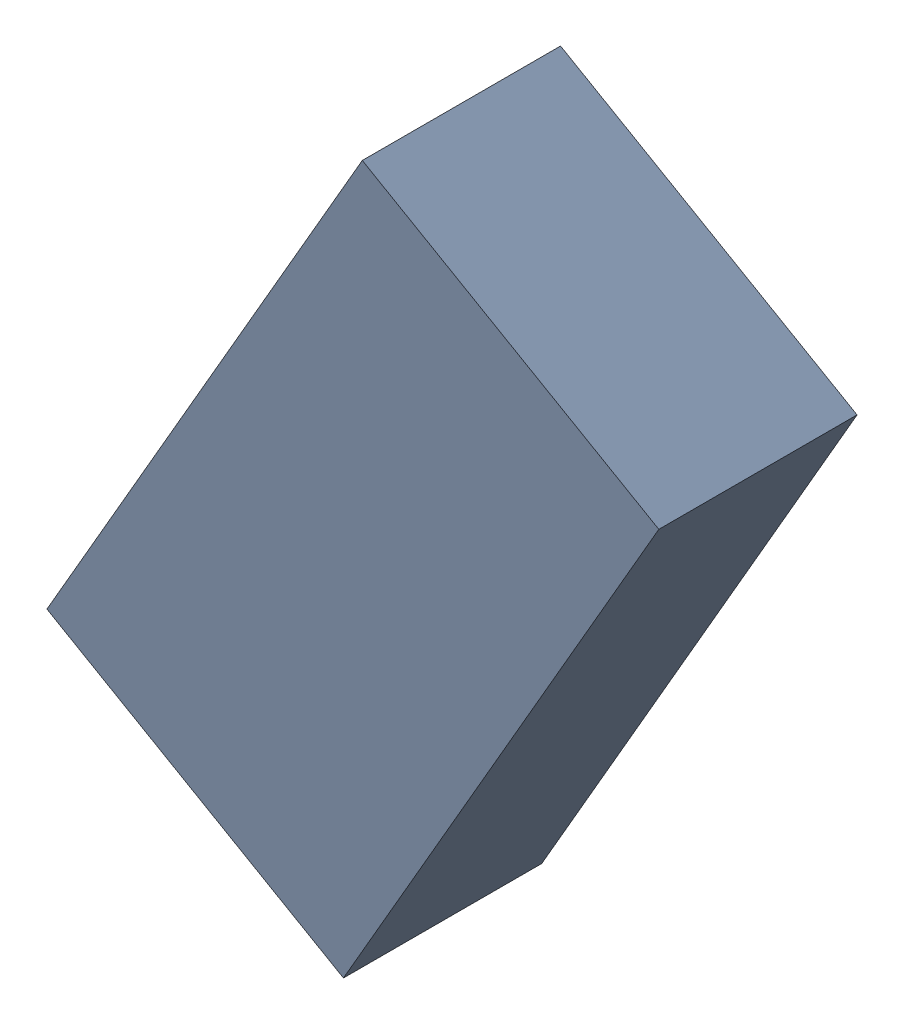
SolidWorks assembly L4_TDA6, configuration Standard. Lengths in mm.
Overall size (1.7 1.99 0.55).
2 component instances, 1 part files, 0 mates.
Components (placement in the parent):
- 885543600-1: 885543600 [Standard] at (-50.1898 31.4611 0) size (1.7 1.99 0.55)
  - Extruded_17-1: Extruded_17 [Standard] at origin size (1.7 1.99 0.55)
